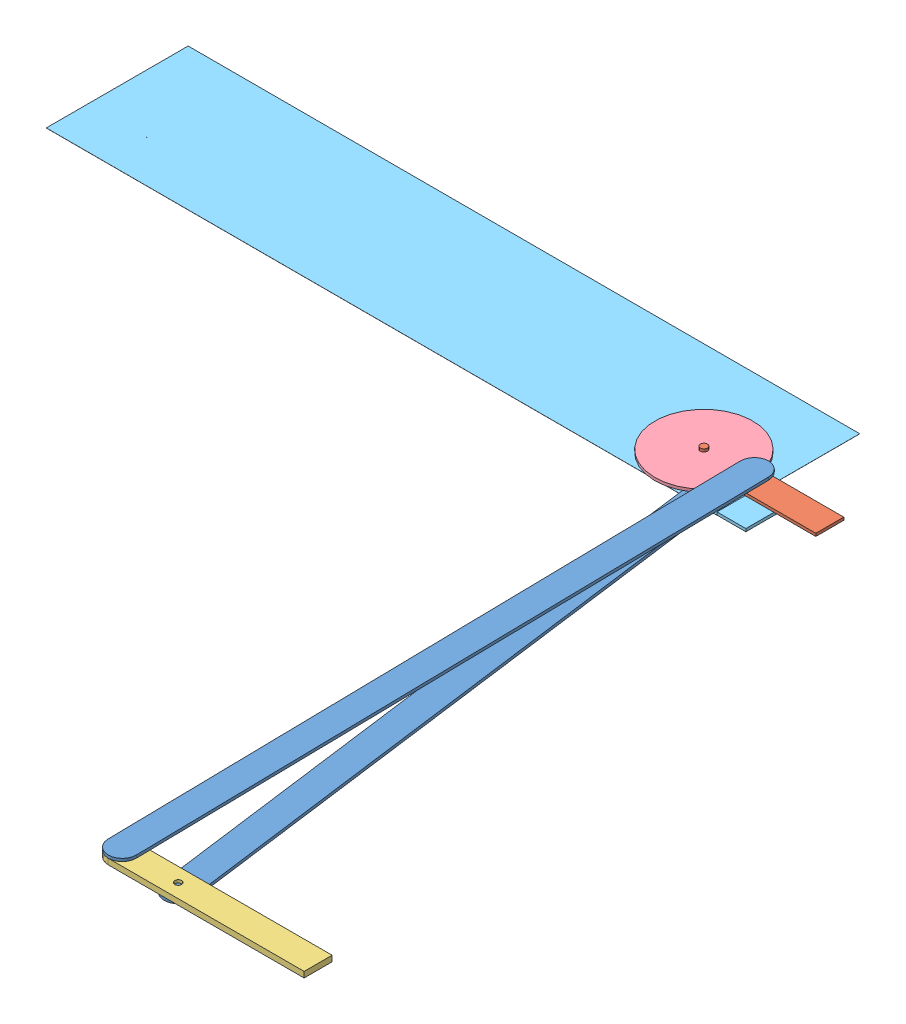
SolidWorks assembly Elevator, configuration Default. Lengths in mm.
Overall size (787.81 10.39 684.09).
6 component instances, 5 part files, 12 mates.
Components (placement in the parent):
- Arm-1: Arm [Default] at (131.617 284.5438 1077.857) x (-0.131132 0 -0.991365) z (0 1 0) size (609.6 25.4 5.08)
- foot-1: foot [Default] at (4.3195 287.2108 513.067) size (127 10.16 25.4)
- foot 2-1: foot 2 [Default] at (68.2267 287.0838 1092.2224) x (1 0 0) z (0 1 0) size (190.5 25.4 5.21)
- Wheel-1: Wheel [Default] at (17.0195 292.2908 500.367) x (-0.992768 0 0.120049) z (0 -1 0) size (92.08 88.9 2.54)
- Arm-2: Arm [Default] at (55.5286 294.8308 1079.7448) x (-0.017512 0 -0.999847) z (0 -1 0) size (609.6 25.4 5.08)
- frame-2: frame [Default] at (-541.7805 284.5438 409.689) x (1 0 0) z (0 -1 0) size (635 128.78 2.64)
Mates (geometry in assembly coordinates):
- Concentric1: concentric: cylinder of foot-1 through (17.0195 294.8308 500.367) axis (0 -1 0) radius 3.175; cylinder of Wheel-1 through (17.0195 289.7508 500.367) axis (0 1 0) radius 3.175
- Coincident1: coincident: plane of foot-1 through (4.3195 289.7508 513.067) normal (0 1 0); plane of Wheel-1 through (17.0195 289.7508 500.367) normal (0 -1 0)
- Coincident2: coincident: plane of Wheel-1 through (17.0195 292.2908 500.367) normal (0 1 0); plane of Arm-2 through (55.5286 292.2908 1079.7448) normal (0 -1 0)
- Concentric2: concentric: cylinder of Wheel-1 through (57.996 289.7508 495.412) axis (0 1 0) radius 3.175; cylinder of Arm-2 through (57.996 289.7508 495.412) axis (0 1 0) radius 3.175
- Coincident3: coincident: plane of foot 2-1 through (68.2267 292.2908 1092.2224) normal (0 1 0); plane of Arm-2 through (55.5286 292.2908 1079.7448) normal (0 -1 0)
- Concentric3: concentric: cylinder of foot 2-1 through (68.2267 292.2908 1079.5224) axis (0 -1 0) radius 3.175; cylinder of Arm-2 through (68.2267 289.7508 1079.5224) axis (0 1 0) radius 3.175
- Coincident7: coincident: plane of Arm-1 through (131.617 287.0838 1077.857) normal (0 1 0); plane of foot 2-1 through (68.2267 287.0838 1092.2224) normal (0 -1 0)
- Concentric8: concentric: cylinder of Arm-1 through (119.0267 289.6238 1079.5224) axis (0 -1 0) radius 3.175; cylinder of foot 2-1 through (119.0267 292.2908 1079.5224) axis (0 -1 0) radius 3.175
- Concentric9: concentric: cylinder of Arm-1 through (42.4195 289.6238 500.367) axis (0 -1 0) radius 3.175; cylinder of foot-1 through (42.4195 284.6708 500.367) axis (0 1 0) radius 3.175
- Concentric10: concentric: circle of foot-1; circle of frame-2
- Coincident9: coincident: plane of Arm-1 through (131.617 284.5438 1077.857) normal (0 -1 0); plane of frame-2 through (-541.7805 284.5438 409.689) normal (0 1 0)
- Parallel8: parallel: line of foot-1 through (4.3195 289.7508 513.067) axis (1 0 0); line of foot 2-1 through (68.2267 292.2908 1092.2224) axis (1 0 0)
